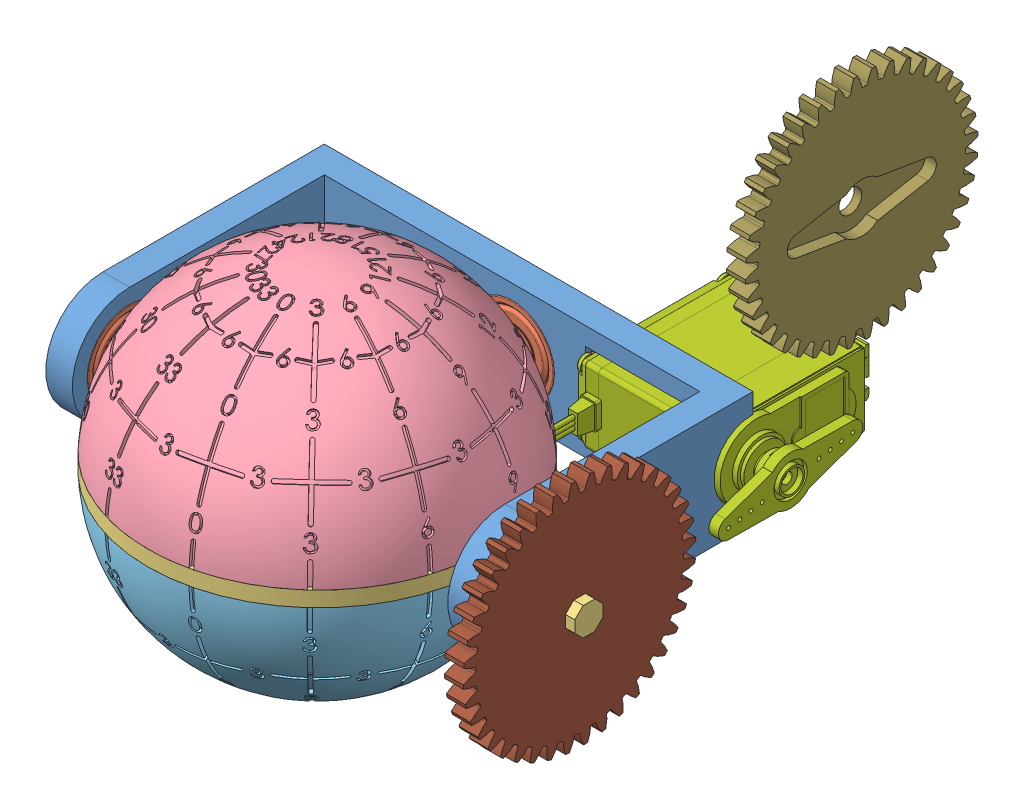
SolidWorks assembly Pitch, configuration Default. Lengths in mm.
Overall size (179.03 179.03 194.04).
16 component instances, 12 part files, 15 mates.
Components (placement in the parent):
- PitchBracket-1: PitchBracket [Default] at (31.7712 60.6007 112.0245) size (112.5 30 73.12)
- Ball Bearing 608ZZ-1: Ball Bearing 608ZZ [Défaut] at (-20.9788 60.6007 110.1495) x (0 0 -1) z (1 0 0) size (22 22 7)
- Ball Bearing 608ZZ-2: Ball Bearing 608ZZ [Défaut] at (31.7712 60.6007 55.5245) size (22 22 7)
- Ball Bearing 608ZZ-3: Ball Bearing 608ZZ [Défaut] at (84.5212 60.6007 110.1495) x (0 0 -1) z (1 0 0) size (22 22 7)
- plate-1: plate [Default] at (31.7908 60.6007 110.1495) x (0.678648 0.734461 0.001925) z (0.369415 -0.343605 0.863405) size (138.24 147.99 129.73)
  - BallPlate-1: BallPlate [Default] x (0.678648 -0.634798 0.369415) z (0.007266 0.508751 0.860883) size (127.54 8 88.9)
  - Ball_V9_final_Top-1: Ball_V9_final_Top [Default] x (0.658953 -0.734427 0.162472) z (0.162472 0.349875 0.9226) size (88.8 42.45 88.81)
  - Ball_V9_final_Bot-1: Ball_V9_final_Bot [Default] x (0.658953 -0.734427 0.162472) z (0.162472 0.349875 0.9226) size (88.8 87.56 88.81)
  - SKF 625-1: SKF 625 [Default] at (-1.8361 -1.4539 0.8747) x (0.734427 0.581553 -0.349875) z (0.162472 0.349875 0.9226) size (5 16 16)
  - Servo-2: Servo [noHorn] at (1.3234 -9.0246 -17.9389) x (-0.007266 -0.508751 -0.860883) z (0.678648 -0.634798 0.369415) size (19.8 47.23 67)
  - BallShaft-1: BallShaft [Default] at (1.6489 1.3057 -0.7855) x (-0.141735 -0.372726 -0.917053) z (0.663722 -0.723099 0.191314) size (13.5 16.75 13.5)
  - YawServoGear-1: YawServoGear [Default] at (7.1858 7.691 -27.8667) x (0.658953 -0.734427 0.162472) z (-0.734427 -0.581553 0.349875) size (24.43 24.43 3)
  - BallGear2-2: BallGear2 [Default] at (14.3213 11.3403 -6.8226) x (0.294586 0.191268 0.936288) z (-0.734427 -0.581553 0.349875) size (24.43 24.43 3)
- Servo-1: Servo [Default] at (78.2212 60.6007 41.9676) x (0 1 0) z (0 0 -1) size (19.8 47.23 67)
- PitchGear-1: PitchGear [Default] at (95.6212 60.6007 110.1495) x (0 0 -1) z (1 0 0) size (60.99 60.99 12.6)
- PitchServoGear-1: PitchServoGear [Default] at (95.6212 115.6884 36.0999) x (0 0 -1) z (1 0 0) size (60.99 60.99 5)
Mates (geometry in assembly coordinates):
- Concentric1: concentric: cylinder of PitchBracket-1 through (88.0212 60.6007 110.1495) axis (-1 0 0) radius 11.125; cylinder of Ball Bearing 608ZZ-1 through (214.0714 60.6007 110.1495) axis (1 0 0) radius 11
- Coincident1: coincident: plane of PitchBracket-1 through (-24.4788 75.6007 112.0245) normal (-1 0 0); plane of Ball Bearing 608ZZ-1 through (-24.4788 60.6007 110.1495) normal (-1 0 0)
- Concentric2: concentric: cylinder of PitchBracket-1 through (88.0212 60.6007 110.1495) axis (-1 0 0) radius 11.125; cylinder of Ball Bearing 608ZZ-3 through (319.5714 60.6007 110.1495) axis (1 0 0) radius 11
- Coincident2: coincident: plane of PitchBracket-1 through (88.0212 75.6007 112.0245) normal (1 0 0); plane of Ball Bearing 608ZZ-3 through (88.0212 60.6007 110.1495) normal (1 0 0)
- Concentric3: concentric: cylinder of PitchBracket-1 through (31.7712 60.6007 90.4908) axis (0 0 -1) radius 11.125; cylinder of Ball Bearing 608ZZ-2 through (31.7712 60.6007 290.5748) axis (0 0 1) radius 11
- Coincident3: coincident: plane of PitchBracket-1 through (31.7712 75.6007 52.0245) normal (0 0 -1); plane of Ball Bearing 608ZZ-2 through (31.7712 60.6007 52.0245) normal (0 0 -1)
- Concentric4: concentric: cylinder of Ball Bearing 608ZZ-3 through (319.5714 60.6007 110.1495) axis (1 0 0) radius 4; cylinder of plate-1/BallPlate-1 through (-44.6446 60.6007 110.1495) axis (-1 0 0) radius 4
- Concentric5: concentric: cylinder of Ball Bearing 608ZZ-1 through (214.0714 60.6007 110.1495) axis (1 0 0) radius 4; cylinder of plate-1/BallPlate-1 through (-44.6446 60.6007 110.1495) axis (-1 0 0) radius 4
- Coincident4: coincident: plane of PitchBracket-1 through (-24.4788 75.6007 112.0245) normal (-1 0 0); plane of plate-1/BallPlate-1 through (-24.4788 60.6007 110.1495) normal (-1 0 0)
- Width1: width: plane of PitchBracket-1 through (31.7712 45.6007 112.0245) normal (0 -1 0); plane of PitchBracket-1 through (31.7712 75.6007 112.0245) normal (0 1 0); plane of Servo-1 through (78.2212 50.7007 62.2676) normal (0 -1 0); plane of Servo-1 through (78.2212 70.5007 62.2676) normal (0 1 0)
- Coincident8: coincident: plane of PitchBracket-1 through (81.0212 75.6007 112.0245) normal (-1 0 0); plane of Servo-1 through (81.0212 51.7007 69.2676) normal (1 0 0)
- Coincident9: coincident: plane of Servo-1 through (95.6212 57.891 68.574) normal (-1 0 0); plane of PitchServoGear-1 through (95.6212 115.6884 36.0999) normal (-1 0 0)
- Concentric7: concentric: circle of PitchBracket-1; circle of PitchGear-1
- Coincident11: coincident: plane of PitchGear-1 through (100.6212 60.6007 110.1495) normal (1 0 0); plane of PitchServoGear-1 through (100.6212 115.6884 36.0999) normal (1 0 0)
- Coincident13: coincident: plane of Servo-1 through (95.6212 57.891 68.574) normal (-1 0 0); plane of PitchServoGear-1 through (95.6212 115.6884 36.0999) normal (-1 0 0)
